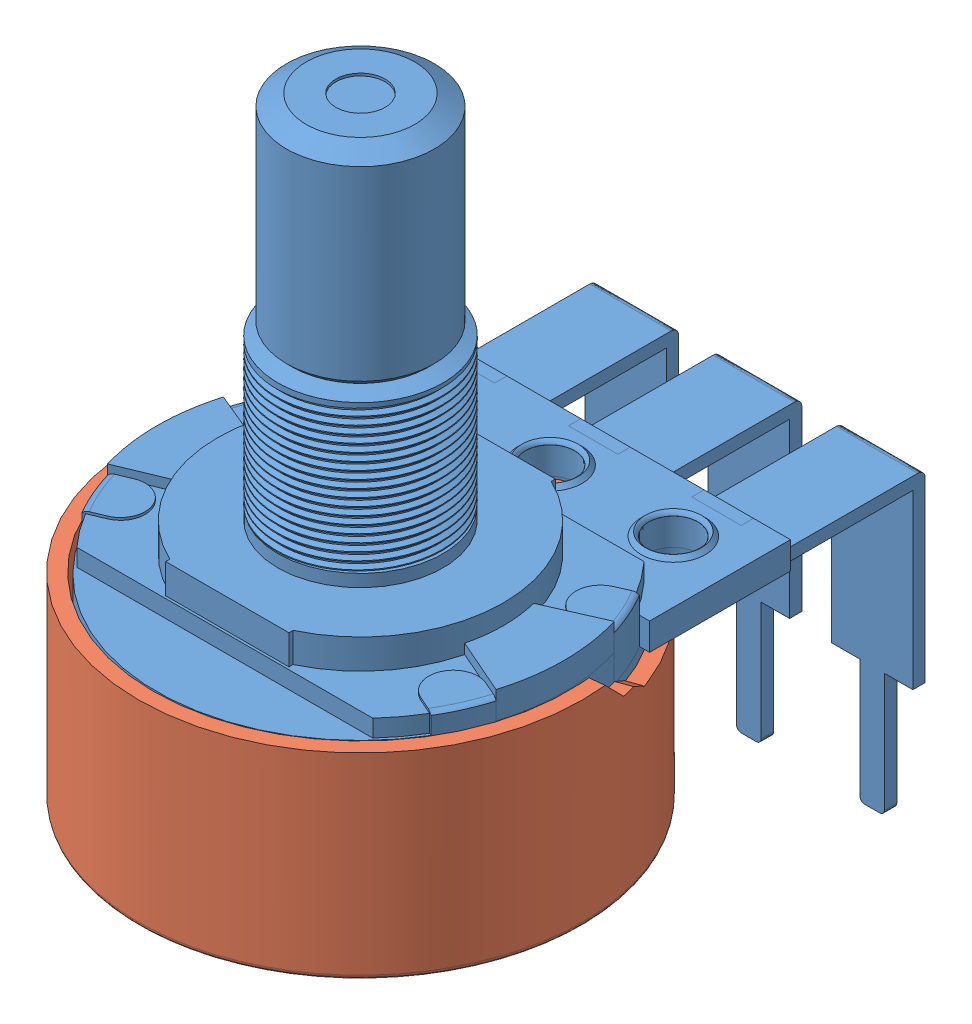
SolidWorks assembly Assem1, configuration Default. Lengths in mm.
Overall size (18 30.5 25.26).
2 component instances, 2 part files, 0 mates.
Components (placement in the parent):
- RV16AF-41-17K-1: RV16AF-41-17K [Default] at (6.5865 11.7282 28.7889) size (16.5 30.5 24.5)
- Cover-1: Cover [Default] at (6.5982 10.9279 28.799) x (-1 0 0) z (0 0 -1) size (18 8 18)
